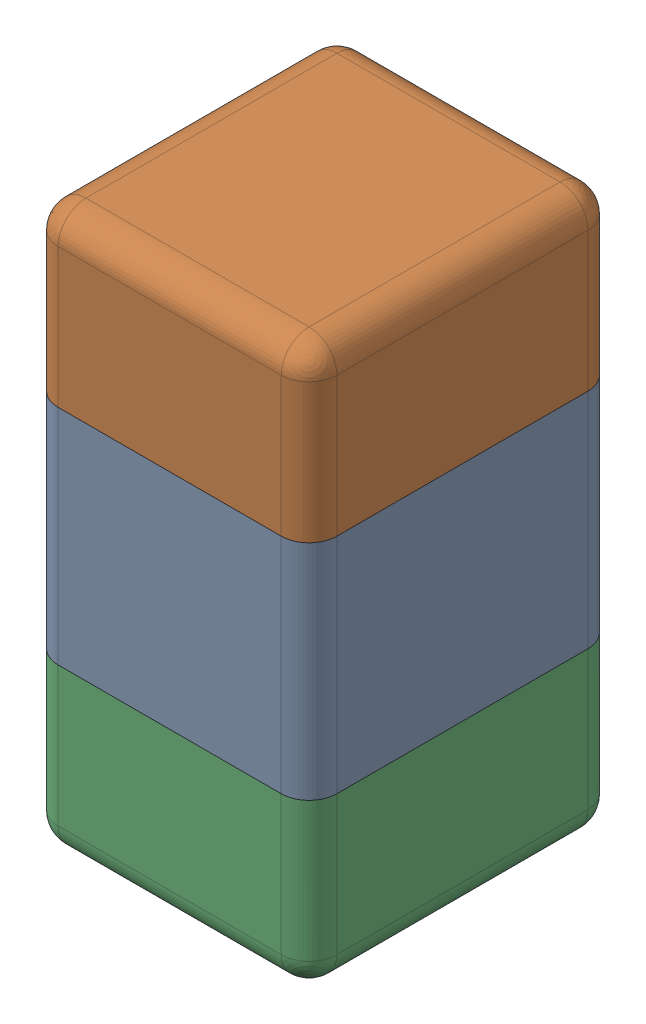
SolidWorks assembly C13, configuration Default. Lengths in mm.
Overall size (0.51 1.01 0.56).
5 component instances, 4 part files, 0 mates.
Components (placement in the parent):
- Cap_Kemet_C0402C562J5RACTU_eec-1: Cap_Kemet_C0402C562J5RACTU_eec [Default] at (152.5 90 -1.6914) x (0 -1 0) z (0 0 -1) size (1.01 0.51 0.56)
  - body_2-1: body_2 [Default] at origin size (0.4 0.5 0.55)
  - terminals-1: terminals [Default] at origin size (0.31 0.51 0.56)
  - terminals_2-1: terminals_2 [Default] at origin size (0.31 0.51 0.56)
  - value-1: value [Default] at (0 0 0.55) size (0.37 0.29 0.15)
